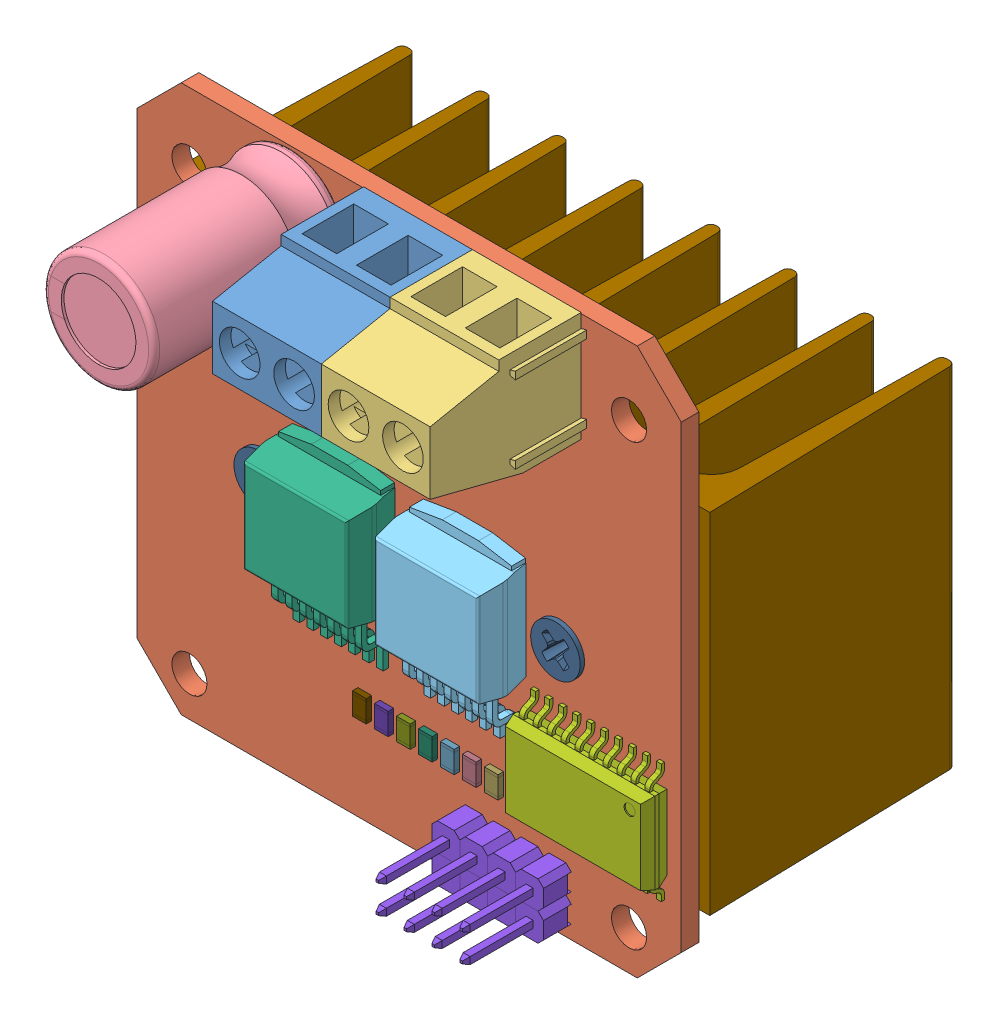
SolidWorks assembly BTS7960 H-Bridge Module, configuration Default. Lengths in mm.
Overall size (51.5 49.9 42).
20 component instances, 18 part files, 0 mates.
Components (placement in the parent):
- BTS7960 H-Bridge Module.step-1: BTS7960 H-Bridge Module.step [Default] at origin size (51.5 49.9 42)
  - 2Pos Terminal Block_001.step-1: 2Pos Terminal Block_001.step [Default] at (0.8 20 1.6) x (0 1 0) z (0 0 1) size (10 10.4 16.75)
  - Body_001.step-1: Body_001.step [Default] at origin size (49.5 49.8 1.6)
  - 2Pos Terminal Block_002.step-1: 2Pos Terminal Block_002.step [Default] at (10.7 20 1.6) x (0 1 0) z (0 0 1) size (10 10.4 16.75)
  - Capacitor_001.step-1: Capacitor_001.step [Default] at (-10.7672 19.837 1.6) x (0 -1 0) z (-1 0 0) size (10.12 17.5 10.12)
  - BTN7960_001.step-1: BTN7960_001.step [Default] at (5.9321 -1.893 1.6) size (10 15.38 4.4)
  - BTN7960_002.step-1: BTN7960_002.step [Default] at (-5.9827 -1.8968 1.6) size (10 15.38 4.4)
  - SOJ 20_001.step-1: SOJ 20_001.step [Default] at (17.2939 -12.0721 1.6) x (0 -1 0) z (0 0 1) size (10.85 12.9 2.4)
  - 2x4 Male Header_001.step-1: 2x4 Male Header_001.step [Default] at (5.8669 -22.8725 1.6) size (10.16 5.08 11.3)
  - Fillet.step-1: Fillet.step [Default] at origin size (51.5 31.77 22.9)
  - M2.5x6-Screw.step-1: M2.5x6-Screw.step [Default] at (-13.3 -2.4 2) size (4.5 4.5 6)
  - M2.5x6-Screw.step-2: M2.5x6-Screw.step [Default] at (13.7 -2.4 2) size (4.5 4.5 6)
  - 0805 Resistor_001.step-1: 0805 Resistor_001.step [Default] at (9.9588 -15.7217 1.6) x (0 -1 0) z (0 0 1) size (2 1.25 0.5)
  - 0805 Resistor_002.step-1: 0805 Resistor_002.step [Default] at (7.9588 -15.7217 1.6) x (0 -1 0) z (0 0 1) size (2 1.25 0.5)
  - 0805 Resistor_003.step-1: 0805 Resistor_003.step [Default] at (5.9588 -15.7217 1.6) x (0 -1 0) z (0 0 1) size (2 1.25 0.5)
  - 0805 Resistor_004.step-1: 0805 Resistor_004.step [Default] at (3.9588 -15.7217 1.6) x (0 -1 0) z (0 0 1) size (2 1.25 0.5)
  - 0805 Resistor_005.step-1: 0805 Resistor_005.step [Default] at (1.9588 -15.7217 1.6) x (0 -1 0) z (0 0 1) size (2 1.25 0.5)
  - 0805 Resistor_006.step-1: 0805 Resistor_006.step [Default] at (-0.0412 -15.7217 1.6) x (0 -1 0) z (0 0 1) size (2 1.25 0.5)
  - 0805 Resistor_007.step-1: 0805 Resistor_007.step [Default] at (-2.0412 -15.7217 1.6) x (0 -1 0) z (0 0 1) size (2 1.25 0.5)
  - 0805 Resistor_008.step-1: 0805 Resistor_008.step [Default] at (-4.0412 -15.7217 1.6) x (0 -1 0) z (0 0 1) size (2 1.25 0.5)
